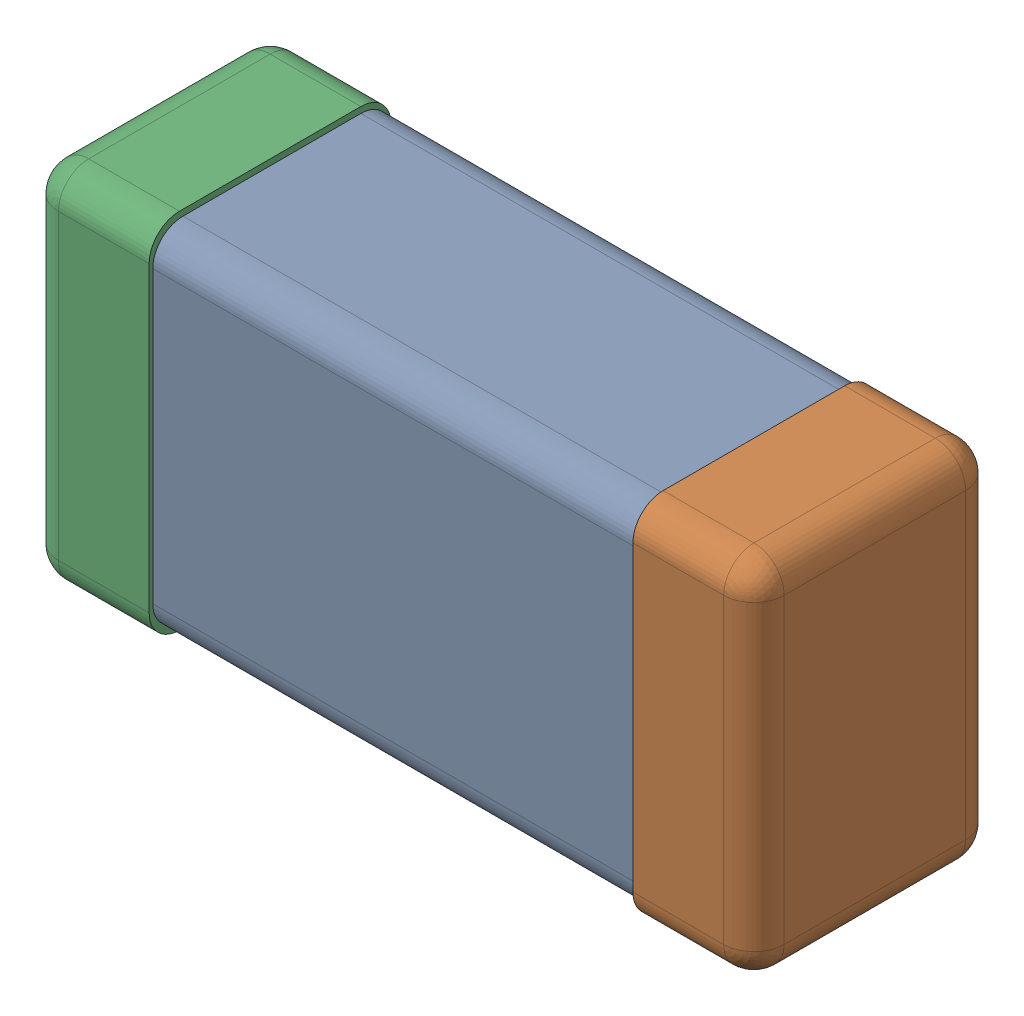
SolidWorks assembly C0201_020_7, configuration Standard. Lengths in mm.
Overall size (0.6 0.3 0.2).
3 component instances, 3 part files, 0 mates.
Components (placement in the parent):
- Part 3_2-1: Part 3_2 [Standard] at (0 0 -7.3015) size (0.5 0.29 0.2)
- Part 2_2-1: Part 2_2 [Standard] at (0 0 -7.3) size (0.1 0.3 0.2)
- Part 1_2-1: Part 1_2 [Standard] at (0 0 -7.3) size (0.1 0.3 0.2)
